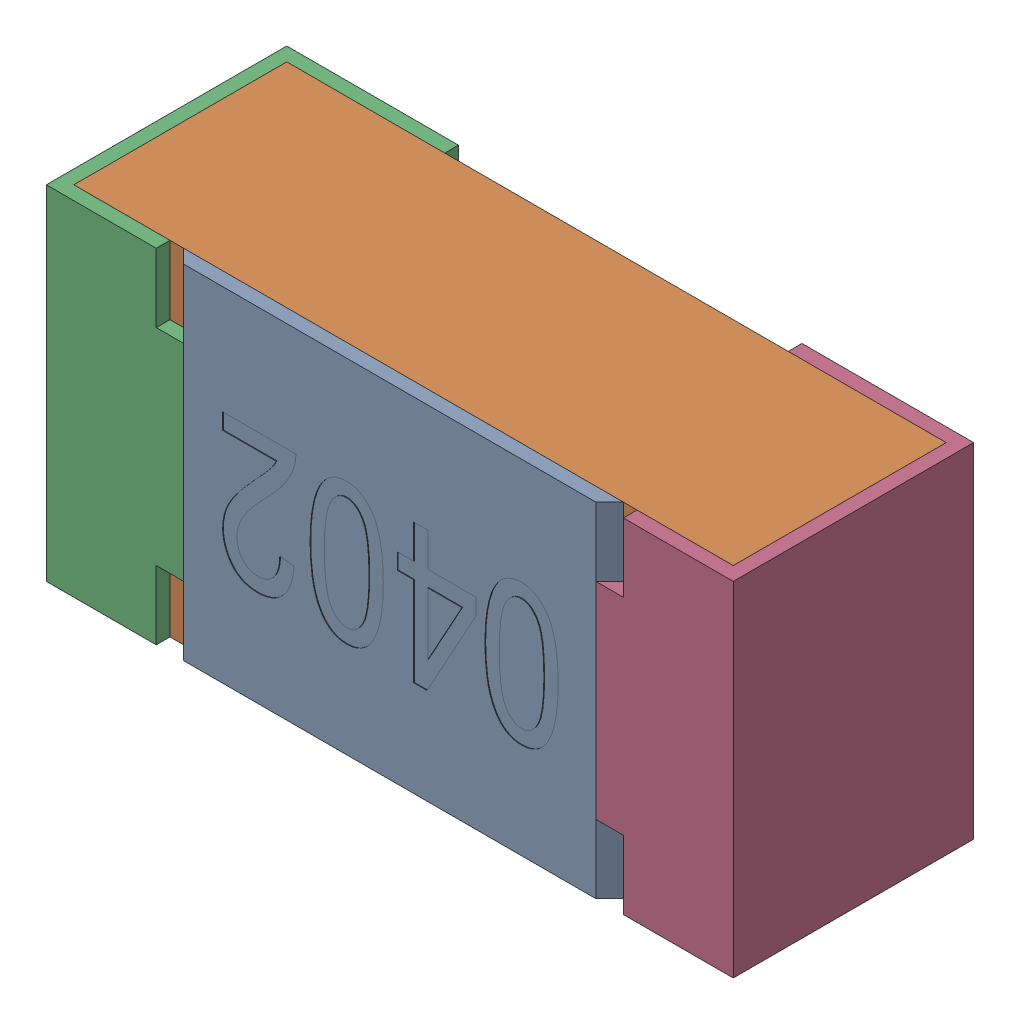
SolidWorks assembly R4, configuration Standard. Lengths in mm.
Overall size (1 0.5 0.35).
5 component instances, 4 part files, 0 mates.
Components (placement in the parent):
- R4-subassembly-1-1: R4-subassembly-1 [Standard] at (12.7999 -17.9 0) x (-1 0 0) z (0 0 1) size (1 0.5 0.35)
  - User Library-R_0402-1: User Library-R_0402 [Standard] at origin size (0.64 0.5 0.02)
  - User Library-R_0402-1-1: User Library-R_0402-1 [Standard] at origin size (0.96 0.5 0.31)
  - User Library-R_0402-2-1: User Library-R_0402-2 [Standard] at origin size (0.25 0.5 0.35)
  - User Library-R_0402-3-1: User Library-R_0402-3 [Standard] at origin size (0.25 0.5 0.35)
